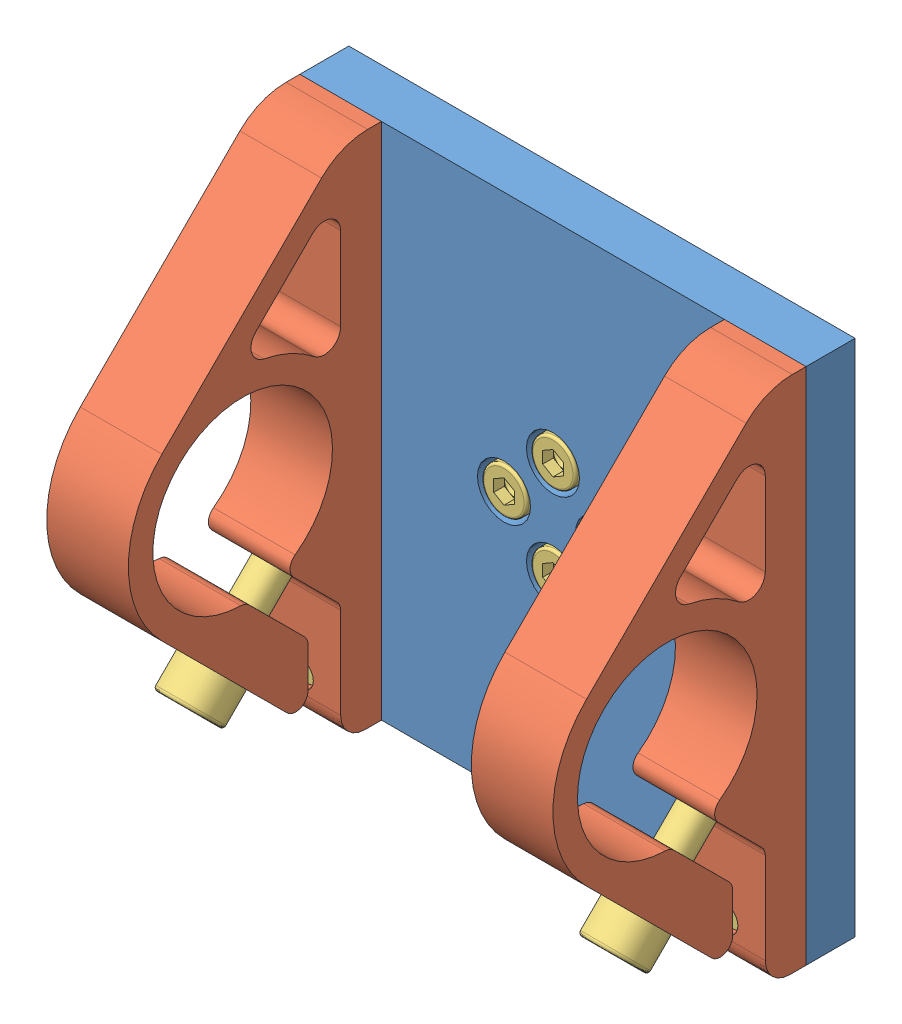
SolidWorks assembly lowcost_handle_holder, configuration По умолчанию. Lengths in mm.
Overall size (62 63.5 46).
13 component instances, 3 part files, 26 mates.
Components (placement in the parent):
- yaw_lowcost_pipe_22mm_holder_plate-1: yaw_lowcost_pipe_22mm_holder_plate [По умолчанию] at (-54.9011 23.534 26.371) size (62 63.5 6)
- pipe_22_holder_3-1: pipe_22_holder_3 [По умолчанию] at (-75.9011 23.534 49.371) x (0 -1 0) z (-1 0 0) size (63.5 31 10)
- pipe_22_holder_3-2: pipe_22_holder_3 [По умолчанию] at (-23.9011 23.534 49.371) x (0 -1 0) z (-1 0 0) size (63.5 31 10)
- socket head cap screw_din_1-1: socket head cap screw_din_1 [DIN 912 M4 x 6 --- 6N] at (-28.9011 -3.216 26.371) x (0 0 1) z (-1 0 0) size (10 7 7)
- socket head cap screw_din_1-2: socket head cap screw_din_1 [DIN 912 M4 x 6 --- 6N] at (-28.9011 50.284 26.371) x (0 0 1) z (-1 0 0) size (10 7 7)
- socket head cap screw_din_1-3: socket head cap screw_din_1 [DIN 912 M4 x 6 --- 6N] at (-80.9011 50.284 26.371) x (0 0 1) z (-1 0 0) size (10 7 7)
- socket head cap screw_din_1-4: socket head cap screw_din_1 [DIN 912 M4 x 6 --- 6N] at (-80.9011 -3.216 26.371) x (0 0 1) z (-1 0 0) size (10 7 7)
- socket head cap screw_din_1-5: socket head cap screw_din_1 [DIN 912 M3 x 12 --- 12N] at (-54.9011 29.534 32.371) x (0 0 -1) z (1 0 0) size (15 5.5 5.5)
- socket head cap screw_din_1-6: socket head cap screw_din_1 [DIN 912 M3 x 12 --- 12N] at (-48.9011 23.534 32.371) x (0 0 -1) z (1 0 0) size (15 5.5 5.5)
- socket head cap screw_din_1-7: socket head cap screw_din_1 [DIN 912 M3 x 12 --- 12N] at (-60.9011 23.534 32.371) x (0 0 -1) z (1 0 0) size (15 5.5 5.5)
- socket head cap screw_din_1-8: socket head cap screw_din_1 [DIN 912 M3 x 12 --- 12N] at (-54.9011 17.534 32.371) x (0 0 -1) z (1 0 0) size (15 5.5 5.5)
- socket head cap screw_din_1-11: socket head cap screw_din_1 [DIN 912 M4 x 16 --- 16N] at (-80.9011 -0.2649 51.0031) x (0 0.707898 -0.706314) z (0.706314 0.499999 0.50112) size (20 7 7)
- socket head cap screw_din_1-12: socket head cap screw_din_1 [DIN 912 M4 x 16 --- 16N] at (-28.9011 -0.2649 51.0031) x (0 0.707898 -0.706314) z (0.706314 0.499999 0.50112) size (20 7 7)
Mates (geometry in assembly coordinates):
- Совпадение1: coincident anti-aligned: plane of yaw_lowcost_pipe_22mm_holder_plate-1 through (-54.9011 23.534 32.371) normal (0 0 1); plane of pipe_22_holder_3-1 through (-85.9011 55.284 32.371) normal (0 0 -1)
- Концентричный1: concentric aligned: cylinder of yaw_lowcost_pipe_22mm_holder_plate-1 through (-80.9011 -3.216 26.371) axis (0 0 -1) radius 2.25; cylinder of pipe_22_holder_3-1 through (-80.9011 -3.216 32.371) axis (0 0 -1) radius 1.65
- Концентричный2: concentric aligned: cylinder of yaw_lowcost_pipe_22mm_holder_plate-1 through (-80.9011 50.284 26.371) axis (0 0 -1) radius 2.25; cylinder of pipe_22_holder_3-1 through (-80.9011 50.284 32.371) axis (0 0 -1) radius 1.65
- Совпадение2: coincident anti-aligned: plane of yaw_lowcost_pipe_22mm_holder_plate-1 through (-54.9011 23.534 32.371) normal (0 0 1); plane of pipe_22_holder_3-2 through (-33.9011 55.284 32.371) normal (0 0 -1)
- Концентричный3: concentric aligned: cylinder of yaw_lowcost_pipe_22mm_holder_plate-1 through (-28.9011 -3.216 26.371) axis (0 0 -1) radius 2.25; cylinder of pipe_22_holder_3-2 through (-28.9011 -3.216 32.371) axis (0 0 -1) radius 1.65
- Концентричный5: concentric aligned: cylinder of yaw_lowcost_pipe_22mm_holder_plate-1 through (-28.9011 50.284 26.371) axis (0 0 -1) radius 2.25; cylinder of pipe_22_holder_3-2 through (-28.9011 50.284 32.371) axis (0 0 -1) radius 1.65
- Концентричный4: concentric aligned: cylinder of yaw_lowcost_pipe_22mm_holder_plate-1 through (-28.9011 -3.216 26.371) axis (0 0 -1) radius 2.25; cylinder of socket head cap screw_din_1-1 through (-28.9011 -3.216 -5.379) axis (0 0 -1) radius 3.5
- Совпадение3: coincident anti-aligned: plane of yaw_lowcost_pipe_22mm_holder_plate-1 through (-26.6511 -3.216 30.371) normal (0 0 -1); plane of socket head cap screw_din_1-1 through (-28.9011 0.284 30.371) normal (0 0 1)
- Совпадение4: coincident anti-aligned: plane of yaw_lowcost_pipe_22mm_holder_plate-1 through (-26.6511 50.284 30.371) normal (0 0 -1); plane of socket head cap screw_din_1-2 through (-28.9011 53.784 30.371) normal (0 0 1)
- Концентричный6: concentric aligned: cylinder of yaw_lowcost_pipe_22mm_holder_plate-1 through (-28.9011 50.284 26.371) axis (0 0 -1) radius 2.25; cylinder of socket head cap screw_din_1-2 through (-28.9011 50.284 -5.379) axis (0 0 -1) radius 3.5
- Концентричный7: concentric aligned: cylinder of yaw_lowcost_pipe_22mm_holder_plate-1 through (-80.9011 50.284 26.371) axis (0 0 -1) radius 2.25; cylinder of socket head cap screw_din_1-3 through (-80.9011 50.284 -5.379) axis (0 0 -1) radius 3.5
- Совпадение5: coincident anti-aligned: plane of yaw_lowcost_pipe_22mm_holder_plate-1 through (-78.6511 50.284 30.371) normal (0 0 -1); plane of socket head cap screw_din_1-3 through (-80.9011 53.784 30.371) normal (0 0 1)
- Концентричный8: concentric aligned: cylinder of yaw_lowcost_pipe_22mm_holder_plate-1 through (-80.9011 -3.216 26.371) axis (0 0 -1) radius 2.25; cylinder of socket head cap screw_din_1-4 through (-80.9011 -3.216 -5.379) axis (0 0 -1) radius 3.5
- Совпадение6: coincident anti-aligned: plane of yaw_lowcost_pipe_22mm_holder_plate-1 through (-78.6511 -3.216 30.371) normal (0 0 -1); plane of socket head cap screw_din_1-4 through (-80.9011 0.284 30.371) normal (0 0 1)
- Концентричный9: concentric aligned: cylinder of yaw_lowcost_pipe_22mm_holder_plate-1 through (-54.9011 29.534 32.371) axis (0 0 1) radius 1.7; cylinder of socket head cap screw_din_1-5 through (-54.9011 29.534 64.121) axis (0 0 1) radius 2.75
- Совпадение7: coincident anti-aligned: plane of yaw_lowcost_pipe_22mm_holder_plate-1 through (-53.2011 29.534 29.371) normal (0 0 1); plane of socket head cap screw_din_1-5 through (-54.9011 32.284 29.371) normal (0 0 -1)
- Совпадение8: coincident anti-aligned: plane of yaw_lowcost_pipe_22mm_holder_plate-1 through (-53.2011 29.534 29.371) normal (0 0 1); plane of socket head cap screw_din_1-6 through (-48.9011 26.284 29.371) normal (0 0 -1)
- Концентричный10: concentric aligned: cylinder of yaw_lowcost_pipe_22mm_holder_plate-1 through (-48.9011 23.534 32.371) axis (0 0 1) radius 3.25; cylinder of socket head cap screw_din_1-6 through (-48.9011 23.534 64.121) axis (0 0 1) radius 2.75
- Концентричный11: concentric aligned: cylinder of yaw_lowcost_pipe_22mm_holder_plate-1 through (-60.9011 23.534 32.371) axis (0 0 1) radius 3.25; cylinder of socket head cap screw_din_1-7 through (-60.9011 23.534 64.121) axis (0 0 1) radius 2.75
- Совпадение9: coincident anti-aligned: plane of yaw_lowcost_pipe_22mm_holder_plate-1 through (-53.2011 29.534 29.371) normal (0 0 1); plane of socket head cap screw_din_1-7 through (-60.9011 26.284 29.371) normal (0 0 -1)
- Концентричный12: concentric aligned: circle of yaw_lowcost_pipe_22mm_holder_plate-1; cylinder of socket head cap screw_din_1-8 through (-54.9011 17.534 64.121) axis (0 0 1) radius 2.75
- Совпадение10: coincident anti-aligned: plane of yaw_lowcost_pipe_22mm_holder_plate-1 through (-53.2011 29.534 29.371) normal (0 0 1); plane of socket head cap screw_din_1-8 through (-54.9011 20.284 29.371) normal (0 0 -1)
- Концентричный15: concentric aligned: cylinder of pipe_22_holder_3-1 through (-80.9011 2.5667 48.1778) axis (0 -0.707898 0.706314) radius 2.25; cylinder of socket head cap screw_din_1-11 through (-80.9011 -22.7407 73.4286) axis (0 -0.707898 0.706314) radius 3.5
- Совпадение13: coincident anti-aligned: plane of pipe_22_holder_3-1 through (-85.9011 -8.216 37.371) normal (0 -0.707898 0.706314); plane of socket head cap screw_din_1-11 through (-83.3787 4.3127 49.9278) normal (0 0.707898 -0.706314)
- Совпадение14: coincident anti-aligned: plane of pipe_22_holder_3-1 through (-85.9011 -8.216 37.371) normal (0 -0.707898 0.706314); plane of socket head cap screw_din_1-12 through (-31.3787 4.3127 49.9278) normal (0 0.707898 -0.706314)
- Концентричный16: concentric aligned: cylinder of pipe_22_holder_3-2 through (-28.9011 2.5667 48.1778) axis (0 -0.707898 0.706314) radius 2.25; cylinder of socket head cap screw_din_1-12 through (-28.9011 -22.7407 73.4286) axis (0 -0.707898 0.706314) radius 3.5
